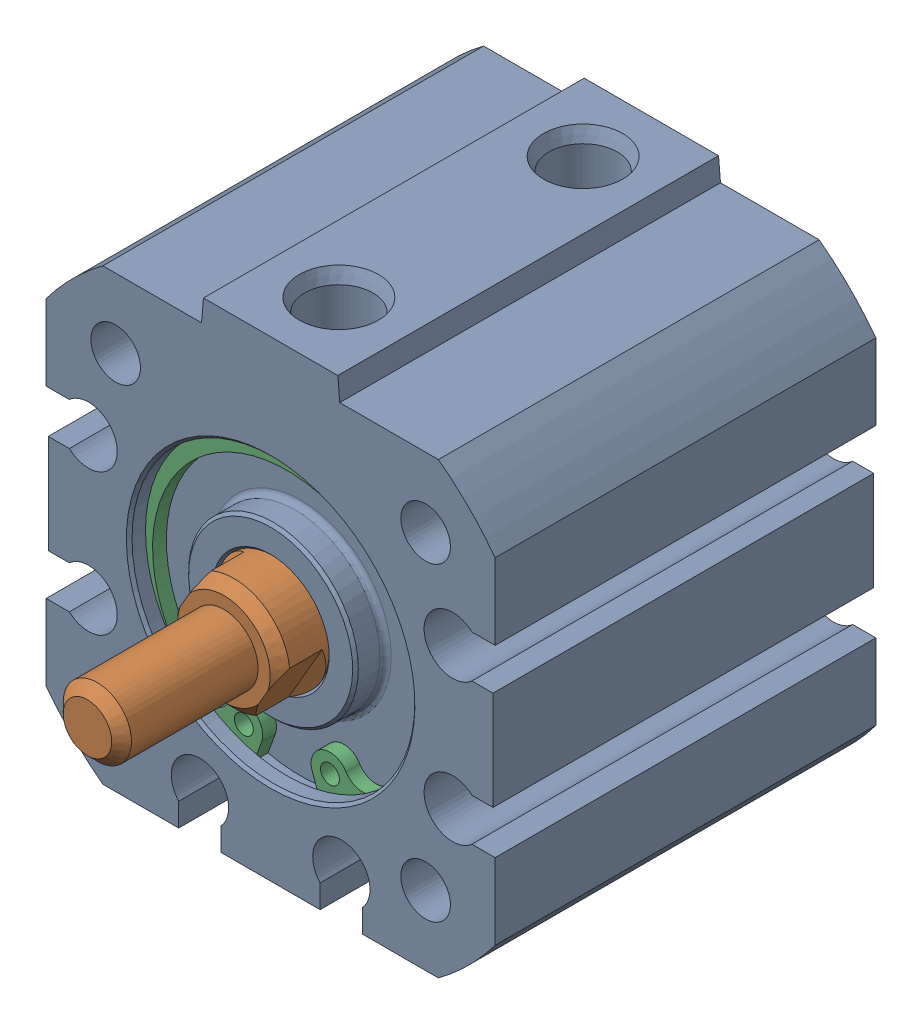
SolidWorks assembly 217-2778-001 Rev2_NCQ8A075-050M, configuration Default. Lengths in mm.
Overall size (31.75 33.34 39.88).
3 component instances, 3 part files, 0 mates.
Components (placement in the parent):
- 217-2778-002_075A-1: 217-2778-002_075A [Default] at origin size (31.75 33.34 26.92)
- 217-2778-003_075M-1: 217-2778-003_075M [Default] at (0 0 -8.85) x (0.866025 -0.5 0) z (0 0 1) size (18.95 18.95 35.27)
- 217-2778-004_075-1: 217-2778-004_075 [Default] at (0 0 10.362) size (21 20.74 0.97)
